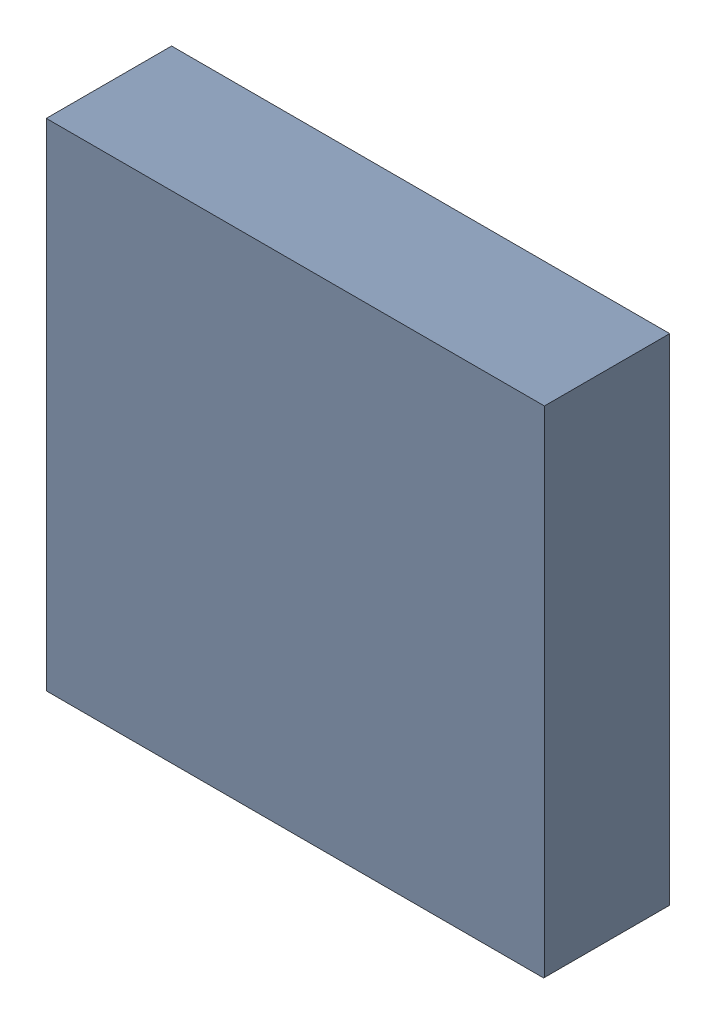
SolidWorks assembly U1, configuration ﾃﾞﾌｫﾙﾄ. Lengths in mm.
Overall size (3.19 3.17 0.82).
4 component instances, 2 part files, 0 mates.
Components (placement in the parent):
- 6641441568-1: 6641441568 [ﾃﾞﾌｫﾙﾄ] at (6.25 17.0875 -2.7339) size (3.19 3.17 0.81)
  - Extruded-21-1: Extruded-21 [ﾃﾞﾌｫﾙﾄ] at origin size (3.19 3.17 0.81)
- 6641441328-1: 6641441328 [ﾃﾞﾌｫﾙﾄ] at (7.5108 18.3998 -2.7339) x (-1 0 0) z (0 0 -1) size (0.2 0.2 0.01)
  - Cylinder-22-1: Cylinder-22 [ﾃﾞﾌｫﾙﾄ] at origin size (0.2 0.2 0.01)
